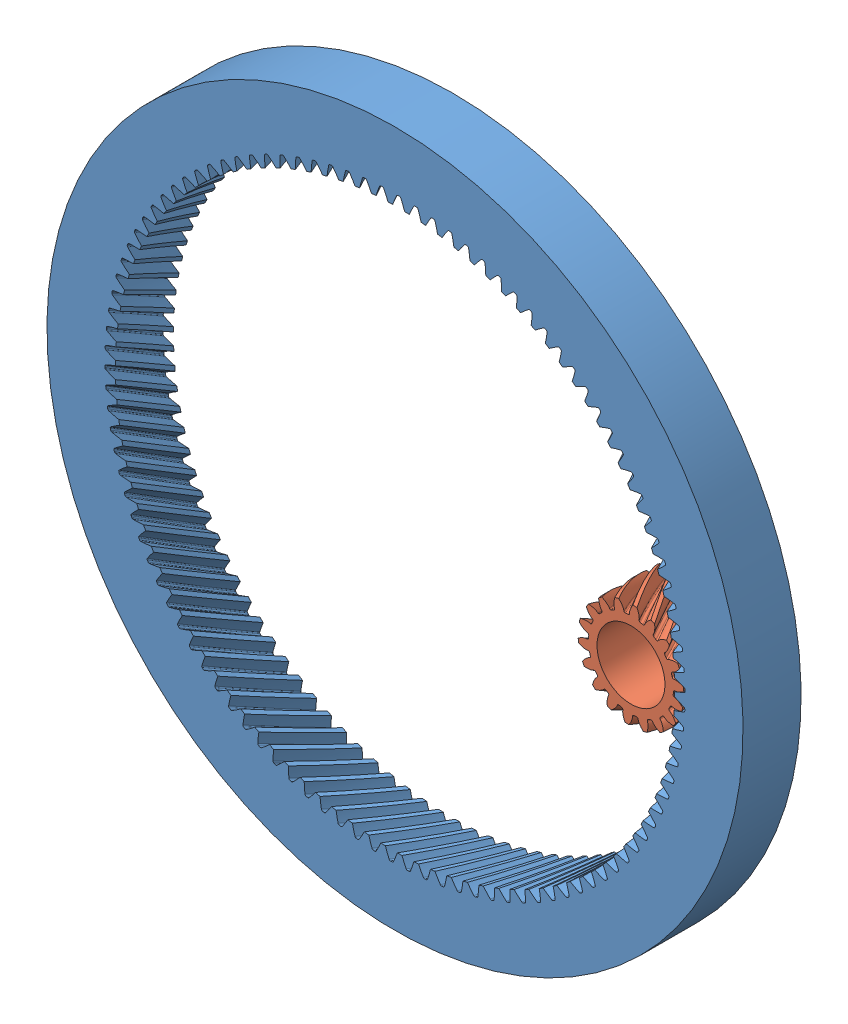
SolidWorks assembly Assemblage1, configuration Défaut. Lengths in mm.
Overall size (77.87 65.93 5).
2 component instances, 2 part files, 7 mates.
Components (placement in the parent):
- couronne hélicoïdale-1: couronne hélicoïdale [creux normal] x (0.994433 0.105368 0) z (0 0 1) size (59.95 59.95 5)
- pignon hélicoïdal-1: pignon hélicoïdal [creux normal] at (20.3227 0 0) x (0.813159 0.582041 0) z (0 0 1) size (31.56 9.42 5)
Mates (geometry in assembly coordinates):
- Coïncidente1: coincident aligned: plane of couronne hélicoïdale-1 through (0 0 0) normal (0 0 1); plane of pignon hélicoïdal-1 through (20.3227 0 0) normal (0 0 1)
- Tangent1: tangent: circle of couronne hélicoïdale-1; circle of pignon hélicoïdal-1
- Contr.Engrenages1: gear = 106 : 18 mm: cylinder of pignon hélicoïdal-1 through (20.3227 0 -5.001) axis (0 0 1) radius 2.9255; cylinder of couronne hélicoïdale-1 through (0 0 -5) axis (0 0 1) radius 29.9756
- Coïncidente3: coincident aligned: plane of couronne hélicoïdale-1 through (0 0 0) normal (0 0 1); plane of assembly through (0 0 0) normal (0 0 1)
- Coïncidente4: coincident: point of couronne hélicoïdale-1; plane of assembly
- Coïncidente5: coincident: point of couronne hélicoïdale-1; plane of assembly
- Coïncidente6: coincident: point of pignon hélicoïdal-1; plane of assembly
